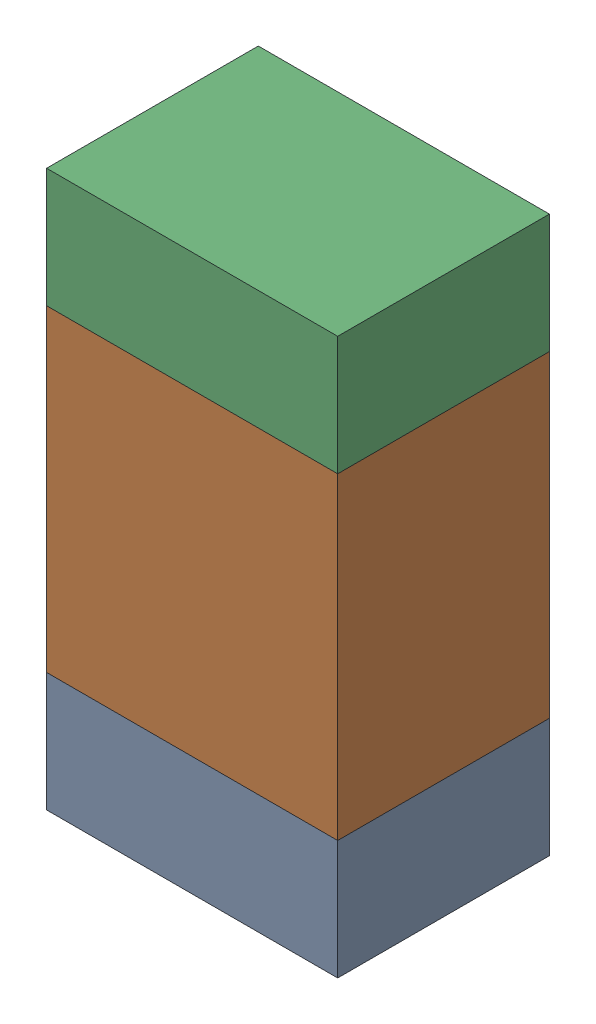
SolidWorks assembly R602_3PCB, configuration Default. Lengths in mm.
Overall size (0.55 1.05 0.4).
6 component instances, 2 part files, 0 mates.
Components (placement in the parent):
- 846483288-1: 846483288 [Default] at (105.6286 94.3376 -2.0638) size (0.55 0.22 0.4)
  - Extruded_12-1: Extruded_12 [Default] at origin size (0.55 0.22 0.4)
- 846483424-1: 846483424 [Default] at (105.6286 94.7501 -2.0638) size (0.55 0.6 0.4)
  - Extruded_13-1: Extruded_13 [Default] at origin size (0.55 0.6 0.4)
- 846483288-2: 846483288 [Default] at (105.6286 95.1626 -2.0638) size (0.55 0.22 0.4)
  - Extruded_12-1: Extruded_12 [Default] at origin size (0.55 0.22 0.4)
